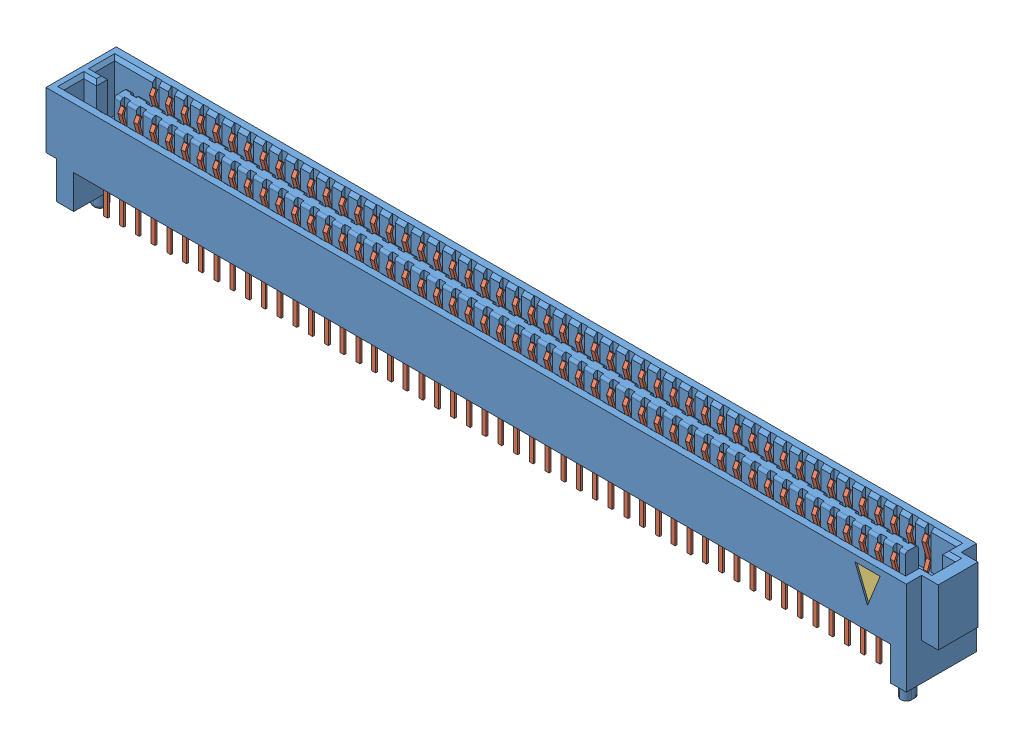
SolidWorks assembly Assem3, configuration Default. Lengths in mm.
Overall size (70.66 8.81 5.66).
5 component instances, 4 part files, 3 mates.
Components (placement in the parent):
- SEAF_50_07_5_L_04_2_A_K_TR-2: SEAF_50_07_5_L_04_2_A_K_TR [Default] at (0.254 2.7178 0) size (70.66 8.81 5.66)
  - _SEAF_50_07_5_L_04_1_A_0_K_TR_BODY_2_2-1: _SEAF_50_07_5_L_04_1_A_0_K_TR_BODY_2_2 [Default] at origin size (70.66 8.81 5.66)
  - _SEAF_50_07_5_L_04_1_A_0_K_TR_cCON2_4-1: _SEAF_50_07_5_L_04_1_A_0_K_TR_cCON2_4 [Default] at origin size (62.55 7.03 5.41)
  - _SEAF_04_K_PAD_6-1: _SEAF_04_K_PAD_6 [Default] at (-0.2286 4.826 0) size (6.5 0.13 6.5) (hidden)
  - _SEAF_TRIANGLE_FIRST_PIN_8-1: _SEAF_TRIANGLE_FIRST_PIN_8 [Default] at (30.861 1.27 2.5781) size (2.03 2.54 0.13)
Mates (geometry in assembly coordinates):
- Coincident1: coincident: plane of ? through (0.254 0 0) normal (0 -1 0)
- Coincident2: coincident: plane of ? through (0.254 2.7178 0) normal (0 0 -1)
- Coincident3: coincident: line of ? through (-3.5801 0 2.7178) axis (0 -1 0)
